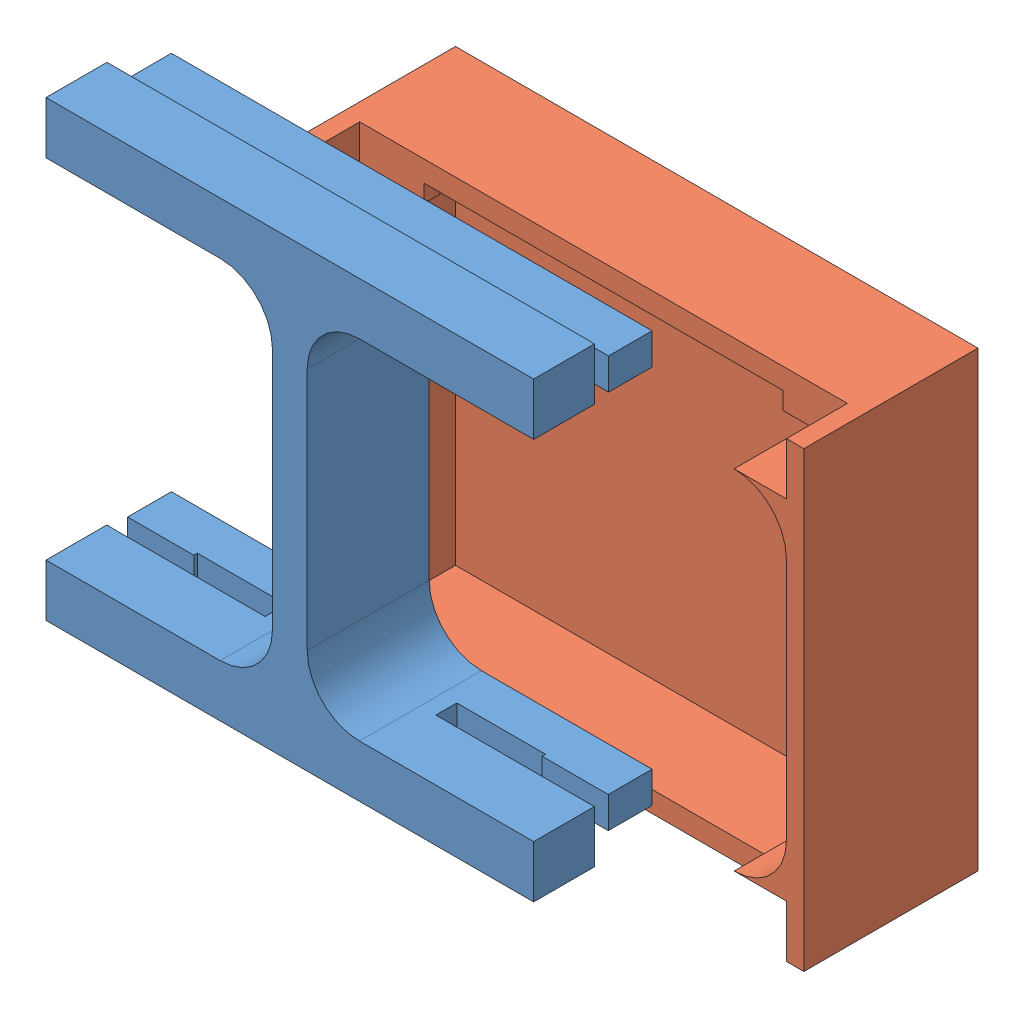
SolidWorks assembly Assem2, configuration Varsayılan. Lengths in mm.
Overall size (37.4 27.82 16.11).
2 component instances, 2 part files, 0 mates.
Components (placement in the parent):
- Part1-1: Part1 [Varsayılan] at (-27.6758 13.4514 2) size (28 26 7)
- Part2-1: Part2 [Varsayılan] at (-17.9475 10.1994 -12.6141) size (30 26 10)
